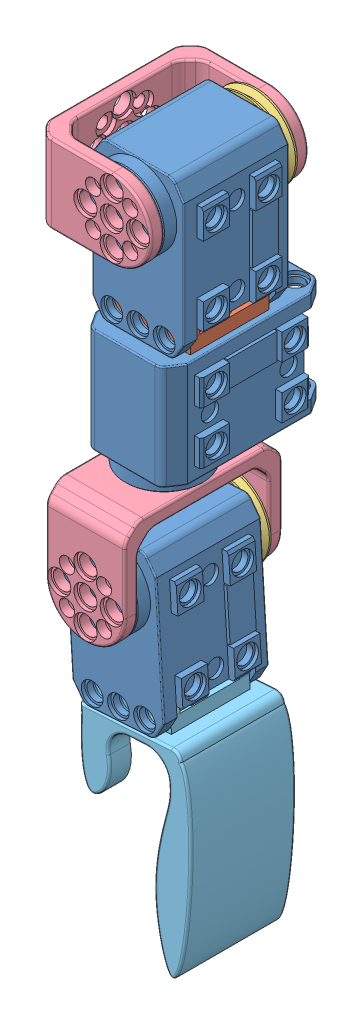
SolidWorks assembly brazo derecho, configuration Predeterminado. Lengths in mm.
Overall size (43.05 159.18 45.15).
9 component instances, 5 part files, 20 mates.
Components (placement in the parent):
- XL-320-1: XL-320 [Default] at origin size (24 36 27)
- SPU-5-1: SPU-5 [Default] at (0 -24 0) x (1 0 0) z (0 -1 0) size (18 18 6)
- SP0-1: SP0 [Default] at (0 0 -13.5) x (1 0 0) z (0 -1 0) size (19 3 19)
- XL-320-2: XL-320 [Default] at (0 -72 6) x (0.99796 0.06384 0) z (0 0 1) size (24 36 27)
- XL-320-3: XL-320 [Default] at (0 -39 6) x (1 0 0) z (0 -1 0) size (24 36 27)
- shoulder-1: shoulder [Default] at origin size (27 18 36.29)
- shoulder-2: shoulder [Default] at (0 -72 6) x (0 -1 0) z (0 0 1) size (27 18 36.29)
- hand-1: hand [left] at (18.7329 -90.9536 35.8813) x (0 0 1) z (0.06384 -0.99796 0) size (32.52 30.29 56.19)
- SP0-2: SP0 [Default] at (0 -72 -7.5) x (1 0 0) z (0 1 0) size (19 3 19)
Mates (geometry in assembly coordinates):
- Coincidente2: coincident anti-aligned: plane of XL-320-1 through (0 0 -12) normal (0 0 -1); plane of SP0-1 through (0 0 -12) normal (0 0 1)
- Concéntrica2: concentric anti-aligned: cylinder of XL-320-1 through (0 0 -12) axis (0 0 -1) radius 2; cylinder of SP0-1 through (0 0 -12) axis (0 0 1) radius 2
- Concéntrica3: concentric aligned: cylinder of XL-320-1 through (0 0 15) axis (0 0 1) radius 2.8; cylinder of shoulder-1 through (0 0 18) axis (0 0 1) radius 2.15
- Coincidente3: coincident anti-aligned: plane of SP0-1 through (0 0 -15) normal (0 0 -1); plane of shoulder-1 through (0 0 -15) normal (0 0 1)
- Coincidente4: coincident aligned: plane of XL-320-1 through (-8 -27 -12) normal (0 -1 0); plane of SPU-5-1 through (0 -27 0) normal (0 -1 0)
- Coincidente5: coincident anti-aligned: plane of XL-320-1 through (0 0 9) normal (0 0 -1); plane of SPU-5-1 through (0 -27 9) normal (0 0 1)
- Concéntrica4: concentric aligned: cylinder of XL-320-1 through (-6 -24 12) axis (0 0 1) radius 2; cylinder of SPU-5-1 through (-6 -24 9) axis (0 0 1) radius 2.5
- Coincidente6: coincident anti-aligned: plane of SPU-5-1 through (0 -27 0) normal (0 -1 0); plane of XL-320-3 through (0 -27 6) normal (0 1 0)
- Concéntrica5: concentric anti-aligned: cylinder of SPU-5-1 through (0 -27 6) axis (0 -1 0) radius 2; cylinder of XL-320-3 through (0 -27 6) axis (0 1 0) radius 2
- Paralelo1: parallel aligned: plane of XL-320-1 through (0 0 12) normal (0 0 1); plane of XL-320-3 through (8 -27 15) normal (0 0 1)
- Coincidente8: coincident anti-aligned: plane of XL-320-3 through (0 -54 6) normal (0 -1 0); plane of shoulder-2 through (9 -54 24) normal (0 1 0)
- Concéntrica6: concentric aligned: cylinder of XL-320-3 through (0 -54 6) axis (0 -1 0) radius 2.8; cylinder of shoulder-2 through (0 -57 6) axis (0 -1 0) radius 2.15
- Coincidente9: coincident anti-aligned: plane of XL-320-2 through (0 -72 21) normal (0 0 1); plane of shoulder-2 through (0 -72 21) normal (0 0 -1)
- Concéntrica7: concentric aligned: cylinder of XL-320-2 through (0 -72 21) axis (0 0 1) radius 2.8; cylinder of shoulder-2 through (0 -72 24) axis (0 0 1) radius 2.15
- Coincidente10: coincident: plane of shoulder-2 through (0 -72 -9) normal (0 0 1); plane of SP0-2 through (0 -72 -9) normal (0 0 -1)
- Coincidente11: coincident: plane of shoulder-2 through (0 -72 -9) normal (0 0 1); plane of SP0-2 through (0 -72 -9) normal (0 0 -1)
- Concéntrica8: concentric aligned: cylinder of shoulder-2 through (0 -72 -12) axis (0 0 -1) radius 2.15; cylinder of SP0-2 through (0 -72 -9) axis (0 0 -1) radius 2
- Coincidente12: coincident: plane of XL-320-2 through (0 -72 15) normal (0 0 -1); plane of hand-1 through (1.7237 -98.9449 15) normal (0 0 1)
- Concéntrica9: concentric: cylinder of XL-320-2 through (-4.4556 -96.3341 18) axis (0 0 1) radius 2; cylinder of hand-1 through (-4.4556 -96.3341 15) axis (0 0 1) radius 2
- Concéntrica10: concentric aligned: cylinder of XL-320-2 through (7.5199 -95.568 18) axis (0 0 1) radius 2; cylinder of hand-1 through (7.5199 -95.568 15) axis (0 0 1) radius 2
